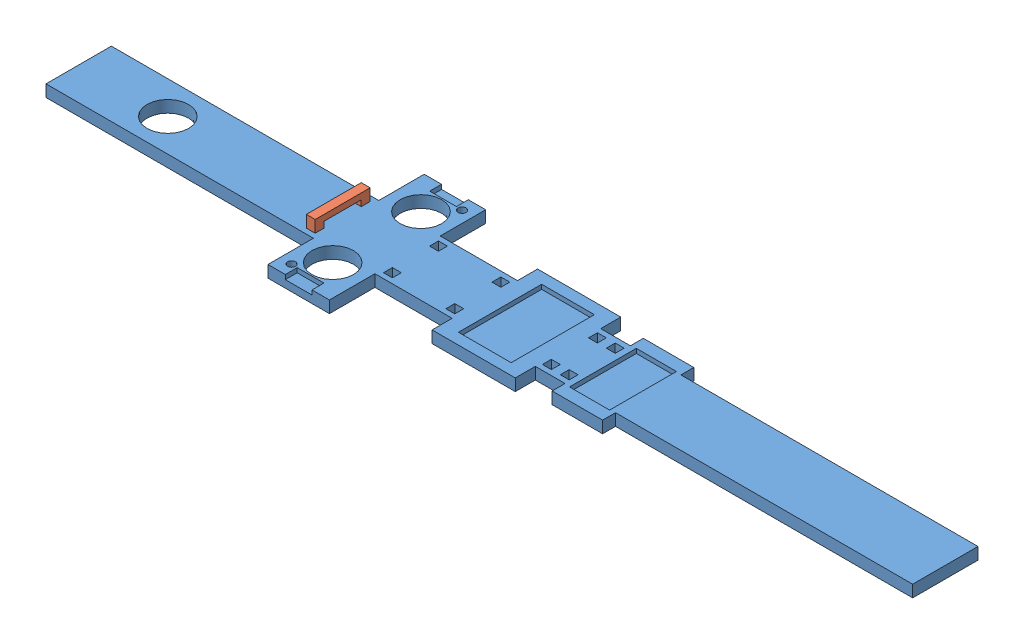
SolidWorks assembly Assem1, configuration Default. Lengths in mm.
Overall size (291.7 8 52.6).
3 component instances, 3 part files, 6 mates.
Components (placement in the parent):
- Bottom-1: Bottom [Default] at (-68.5293 196.8383 287.2136) size (291.7 4 52.6)
- Stopper top-1: Stopper top [Default] at (20.3207 197.8383 266.9636) x (0 0 1) z (-1 0 0) size (18.5 7 3)
- stopper_bottom-2: stopper_bottom [Default] at (17.3207 196.8383 266.2136) x (0 0 1) z (-1 0 0) size (20 3 3)
Mates (geometry in assembly coordinates):
- Coincident1: coincident anti-aligned: plane of Bottom-1 through (17.3207 196.8383 266.9636) normal (1 0 0); plane of Stopper top-1 through (17.3207 197.8383 266.9636) normal (-1 0 0)
- Coincident2: coincident aligned: plane of Bottom-1 through (-68.5293 197.8383 287.2136) normal (0 -1 0); plane of Stopper top-1 through (17.3207 197.8383 269.9636) normal (0 -1 0)
- Coincident3: coincident anti-aligned: plane of Bottom-1 through (17.3207 196.8383 266.9636) normal (0 0 1); plane of Stopper top-1 through (17.3207 197.8383 266.9636) normal (0 0 -1)
- Coincident10: coincident anti-aligned: plane of Bottom-1 through (20.3207 196.8383 266.9636) normal (-1 0 0); plane of stopper_bottom-2 through (20.3207 197.8383 266.2136) normal (1 0 0)
- Coincident11: coincident anti-aligned: plane of Bottom-1 through (17.3207 197.8383 266.2136) normal (0 0 1); plane of stopper_bottom-2 through (17.3207 197.8383 266.2136) normal (0 0 -1)
- Coincident12: coincident aligned: plane of Bottom-1 through (-68.5293 196.8383 287.2136) normal (0 -1 0); plane of stopper_bottom-2 through (17.3207 196.8383 266.2136) normal (0 -1 0)
